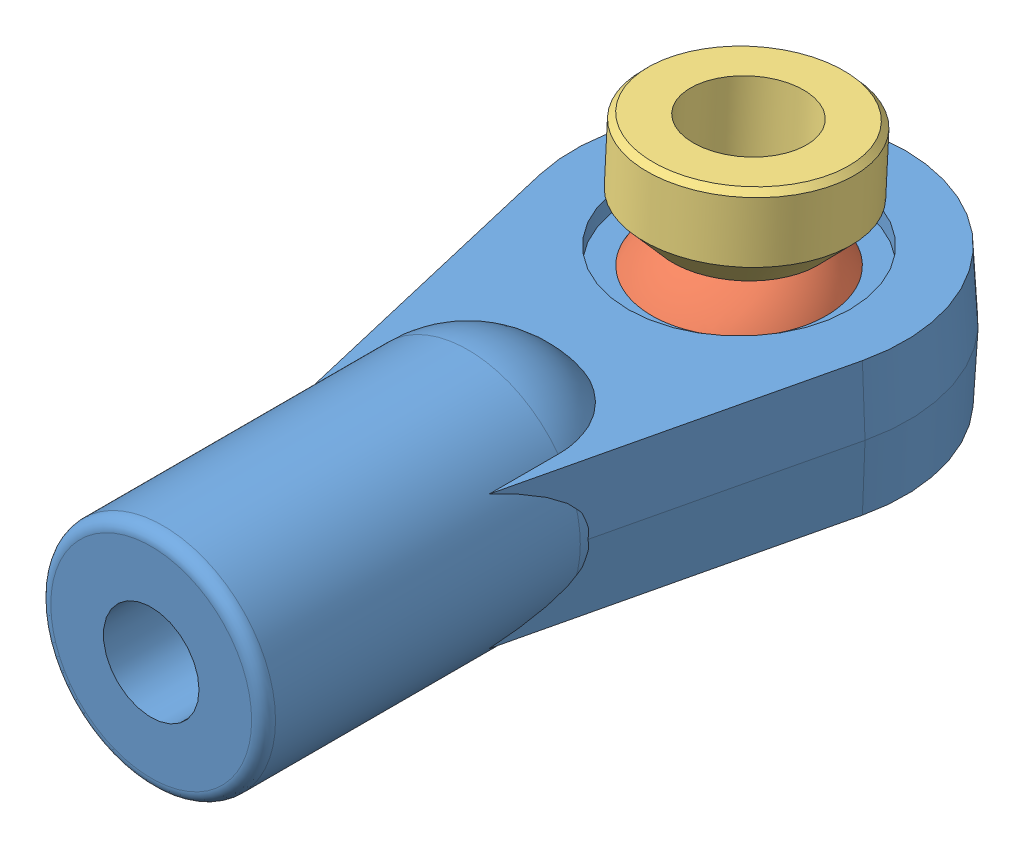
SolidWorks assembly 585432_assembly, configuration Default. Lengths in mm.
Overall size (10.78 9.29 24.13).
3 component instances, 3 part files, 3 mates.
Components (placement in the parent):
- 585432 linkage-1: 585432 linkage [Default] at (-23.1721 -15.566 34.8679) size (10.78 7.16 24.13)
- 585432 ball-1: 585432 ball [Default] at (-23.1721 -15.566 16.129) x (0.977725 0.028162 0.207991) z (-0.209416 0.064365 0.975706) size (6.4 6.4 6.4)
- 585432 spacer-1: 585432 spacer [Default] at (-23.2494 -10.0932 15.7514) x (-0.160981 -0.0702 -0.984458) z (-0.01409 0.997529 -0.068828) size (6.35 6.35 2.98)
Mates (geometry in assembly coordinates):
- Coincident1: coincident: point of 585432 linkage-1; point of 585432 ball-1
- Concentric1: concentric: cylinder of 585432 ball-1 through (-23.127 -18.7585 16.3493) axis (-0.01409 0.997529 -0.068828) radius 1.7399; cylinder of 585432 spacer-1 through (-23.2494 -10.0932 15.7514) axis (0.01409 -0.997529 0.068828) radius 1.7335
- Coincident2: coincident anti-aligned: plane of 585432 ball-1 through (-26.3364 -13.1604 15.2912) normal (-0.01409 0.997529 -0.068828); plane of 585432 spacer-1 through (-23.5651 -13.2263 13.7689) normal (0.01409 -0.997529 0.068828)
